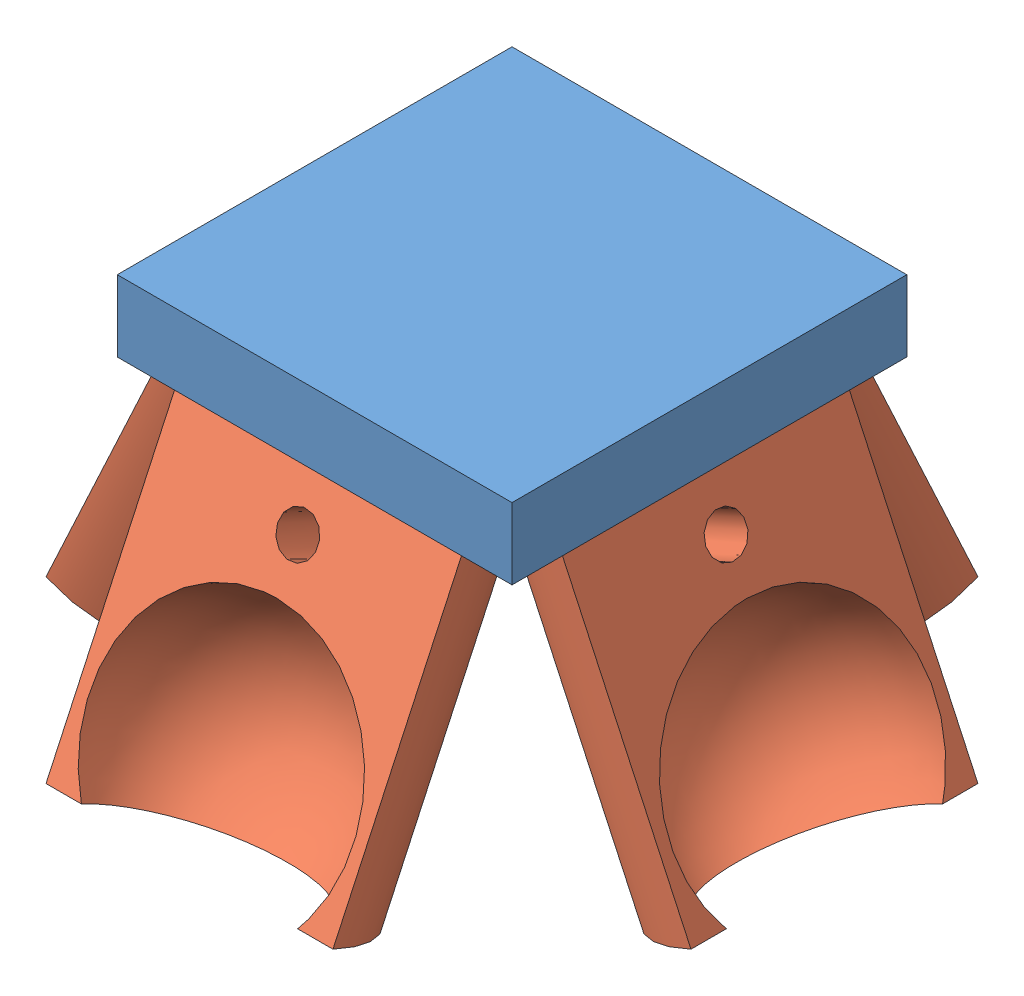
SolidWorks assembly Ensamblaje3, configuration Predeterminado. Lengths in mm.
Overall size (52.29 33.37 52.29).
5 component instances, 2 part files, 12 mates.
Components (placement in the parent):
- Base de 4 puntos_1-1: Base de 4 puntos_1 [Predeterminado] at (30.9374 -0.0261 32.0001) size (32 13.22 32)
- Cilindro de base 4 puntos_6-1: Cilindro de base 4 puntos_6 [Predeterminado] at (-5.0223 -13.9971 71.5583) x (0 -0.906797 0.421568) z (-1 0 0) size (24.84 11.63 23.26)
- Cilindro de base 4 puntos_6-2: Cilindro de base 4 puntos_6 [Predeterminado] at (-5.0223 -13.9979 24.4435) x (0 -0.906797 -0.421568) z (1 0 0) size (24.84 11.63 23.26)
- Cilindro de base 4 puntos_6-3: Cilindro de base 4 puntos_6 [Predeterminado] at (-28.5803 -13.9972 48.0001) x (-0.421568 -0.906797 0) z (0 0 -1) size (24.84 11.63 23.26)
- Cilindro de base 4 puntos_6-4: Cilindro de base 4 puntos_6 [Predeterminado] at (18.529 -14.0004 48.0001) x (0.421568 -0.906797 0) z (0 0 1) size (24.84 11.63 23.26)
Mates (geometry in assembly coordinates):
- Concéntrica1: concentric aligned: circle of Base de 4 puntos_1-1; circle of Cilindro de base 4 puntos_6-1
- Coincidente2: coincident anti-aligned: plane of Base de 4 puntos_1-1 through (-5.0223 2.96 63.675) normal (0 -0.906797 0.421568); plane of Cilindro de base 4 puntos_6-1 through (6.6085 2.96 63.675) normal (0 0.906797 -0.421568)
- Paralelo1: parallel aligned: plane of Base de 4 puntos_1-1 through (-16.6309 2.96 63.675) normal (0 0.421568 0.906797); plane of Cilindro de base 4 puntos_6-1 through (-5.0223 25.7753 53.0682) normal (0 0.421568 0.906797)
- Concéntrica2: concentric aligned: circle of Base de 4 puntos_1-1; circle of Cilindro de base 4 puntos_6-3
- Coincidente3: coincident anti-aligned: plane of Base de 4 puntos_1-1 through (-20.697 2.9599 48.0001) normal (-0.421568 -0.906797 0); plane of Cilindro de base 4 puntos_6-3 through (-20.697 2.9599 59.6308) normal (0.421568 0.906797 0)
- Coincidente4: coincident aligned: plane of Base de 4 puntos_1-1 through (-20.697 2.9599 48.0001) normal (-0.906797 0.421568 0); circle of Cilindro de base 4 puntos_6-3
- Concéntrica3: concentric: circle of Base de 4 puntos_1-1; circle of Cilindro de base 4 puntos_6-2
- Paralelo2: parallel: plane of Base de 4 puntos_1-1 through (30.9374 2.9592 32.3268) normal (0 0.421568 -0.906797); plane of Cilindro de base 4 puntos_6-2 through (-5.0223 25.7745 42.9336) normal (0 0.421568 -0.906797)
- Coincidente7: coincident anti-aligned: plane of Base de 4 puntos_1-1 through (30.9374 2.5535 33.1993) normal (0 -0.906797 -0.421568); plane of Cilindro de base 4 puntos_6-2 through (-16.6531 2.9592 32.3268) normal (0 0.906797 0.421568)
- Concéntrica4: concentric: circle of Base de 4 puntos_1-1; circle of Cilindro de base 4 puntos_6-4
- Coincidente8: coincident: plane of Base de 4 puntos_1-1 through (26.1909 10.1837 32.0001) normal (0.421568 -0.906797 0); plane of Cilindro de base 4 puntos_6-4 through (8.9982 2.1908 36.5121) normal (-0.421568 0.906797 0)
- Coincidente9: coincident aligned: plane of Base de 4 puntos_1-1 through (10.6457 2.9567 32.0001) normal (0.906797 0.421568 0); plane of Cilindro de base 4 puntos_6-4 through (0.0389 25.772 48.0001) normal (0.906797 0.421568 0)
